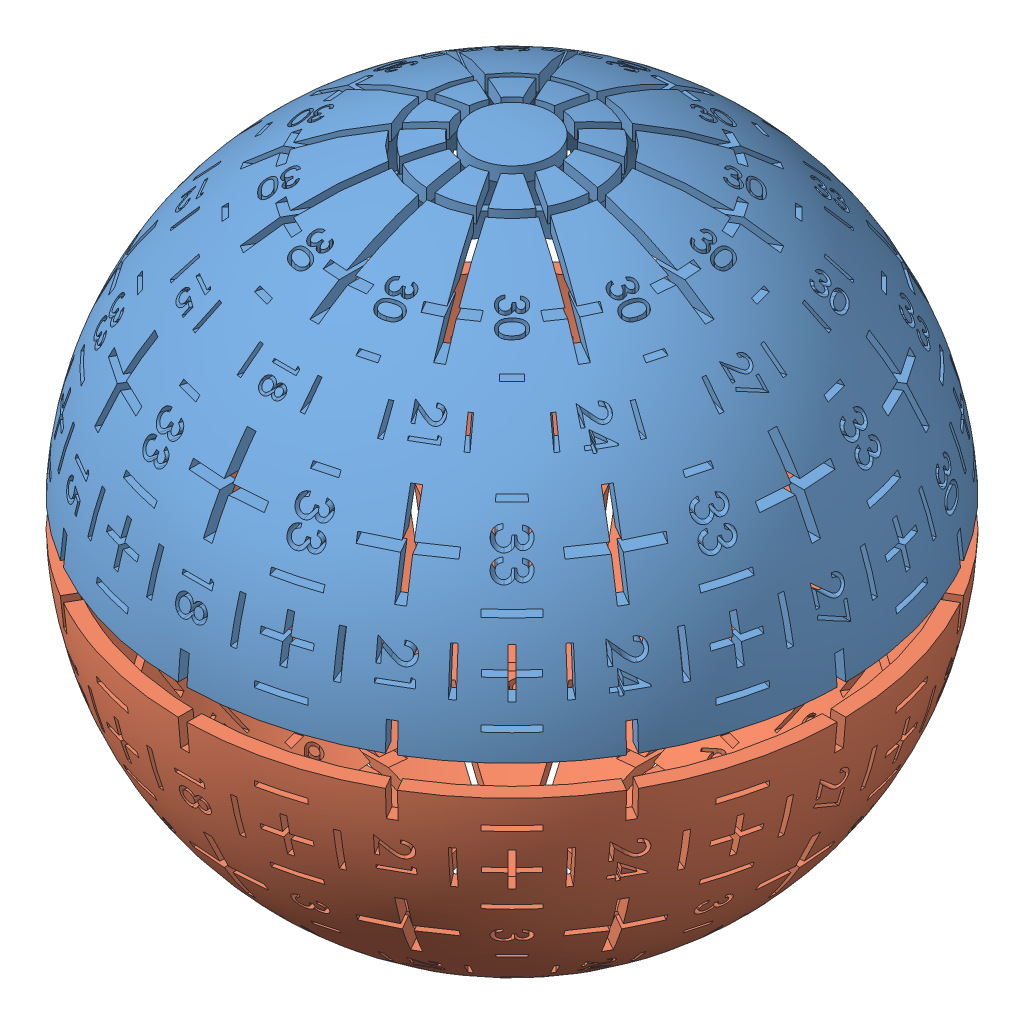
SolidWorks assembly Ballz, configuration Default. Lengths in mm.
Overall size (121.29 88.8 121.29).
2 component instances, 2 part files, 3 mates.
Components (placement in the parent):
- BallV2_Top-1: BallV2_Top [Default] at (-21.5448 -32.4159 17.5791) size (88.79 42.35 88.79)
- BallV2_Bottom-1: BallV2_Bottom [Default] at (-21.5448 -32.3159 17.5791) x (0.5 0 -0.866025) z (-0.866025 0 -0.5) size (88.79 42.35 88.79)
Mates (geometry in assembly coordinates):
- Concentric1: concentric: circle of BallV2_Top-1; circle of BallV2_Bottom-1
- Distance2: distance = 4.1 mm: plane of BallV2_Bottom-1 through (-21.5448 -34.4159 17.5791) normal (0 1 0); plane of BallV2_Top-1 through (-21.5448 -30.3159 17.5791) normal (0 -1 0)
- Coincident4: coincident: plane of BallV2_Top-1 through (17.2435 -26.5639 -4.1377) normal (-0.5 0 -0.866025); plane of BallV2_Bottom-1 through (17.2435 -38.1678 -4.1377) normal (-0.5 0 -0.866025)
